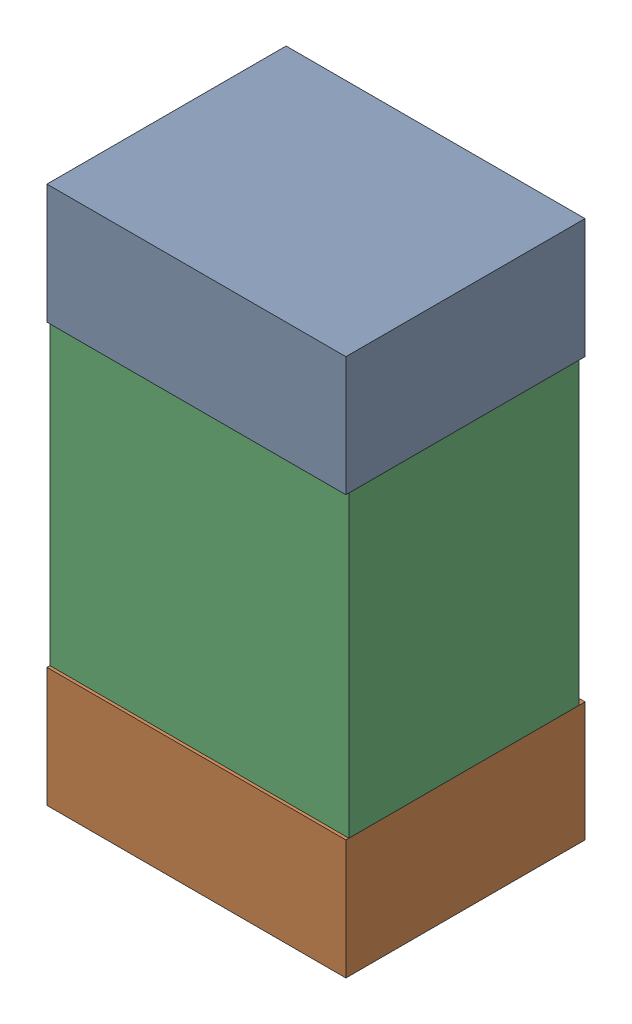
SolidWorks assembly L406PCB, configuration Default. Lengths in mm.
Overall size (1 1.8 0.8).
6 component instances, 2 part files, 0 mates.
Components (placement in the parent):
- 846483560-1: 846483560 [Default] at (114.6001 110.0001 -2.4638) size (1 0.4 0.8)
  - Extruded_17-1: Extruded_17 [Default] at origin size (1 0.4 0.8)
- 846483560-2: 846483560 [Default] at (114.6001 108.6001 -2.4638) size (1 0.4 0.8)
  - Extruded_17-1: Extruded_17 [Default] at origin size (1 0.4 0.8)
- 846483152-1: 846483152 [Default] at (114.6001 109.3001 -2.4438) size (1 1 0.77)
  - Extruded_3-1: Extruded_3 [Default] at origin size (1 1 0.77)
